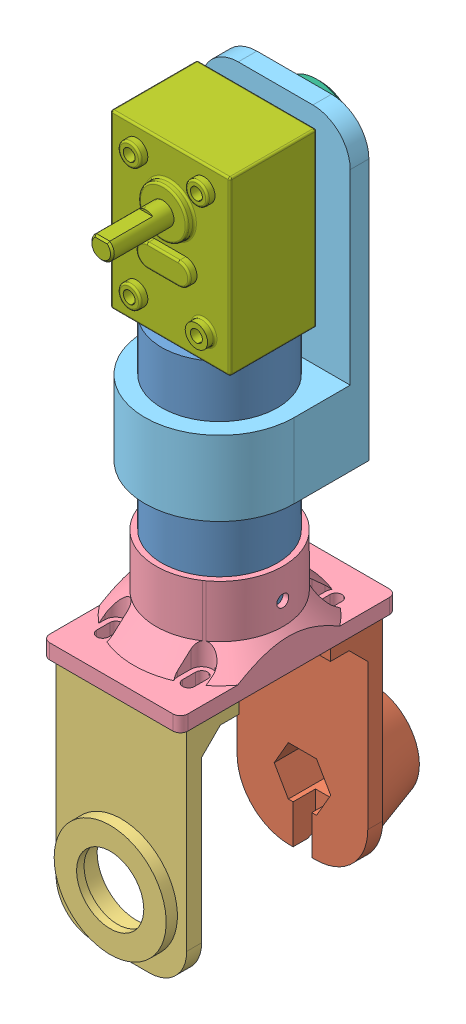
SolidWorks assembly extraLink, configuration По умолчанию. Lengths in mm.
Overall size (40 182 81.54).
7 component instances, 7 part files, 17 mates.
Components (placement in the parent):
- tube2-1: tube2 [По умолчанию] at origin size (31 70 31)
- shaftClamp-1: shaftClamp [По умолчанию] at (-0.0494 -35 -26.25) x (0 1 0) z (1 0 0) size (62 30 35)
- upperBearingClamp-1: upperBearingClamp [По умолчанию] at (-0.0494 -35 26.25) x (0 1 0) z (-1 0 0) size (62 17 35)
- newTubeHolder-1: newTubeHolder [По умолчанию] at (0 -4 0) x (0 0 -1) z (1 0 0) size (58 24 37)
- bearingHolder-2: bearingHolder [По умолчанию] at (0 36 0) x (0 0 -1) z (1 0 0) size (44.5 80 40)
- подшипник-1: подшипник [По умолчанию] at (0 101 -27) x (0.388832 0.921309 0) z (0.921309 -0.388832 0) size (21 5 21)
- двигатель4-1: двигатель4 [По умолчанию] at (0 36.2 0) x (-1 0 0) z (0 0 -1) size (32 79.8 43.9)
Mates (geometry in assembly coordinates):
- Концентричный2: concentric aligned: cylinder of tube2-1 through (0 70 0) axis (0 -1 0) radius 15.5; cylinder of newTubeHolder-1 through (0 20 0) axis (0 -1 0) radius 17
- Совпадение2: coincident anti-aligned: plane of tube2-1 through (0 0 0) normal (0 -1 0); plane of newTubeHolder-1 through (0 0 0) normal (0 1 0)
- Концентричный3: concentric aligned: circle of upperBearingClamp-1; circle of newTubeHolder-1
- Концентричный4: concentric aligned: circle of upperBearingClamp-1; circle of newTubeHolder-1
- Совпадение4: coincident anti-aligned: plane of upperBearingClamp-1 through (-17.5494 -4 22.25) normal (0 1 0); plane of newTubeHolder-1 through (0 -4 0) normal (0 -1 0)
- Концентричный6: concentric aligned: circle of shaftClamp-1; circle of newTubeHolder-1
- Концентричный7: concentric aligned: circle of shaftClamp-1; circle of newTubeHolder-1
- Совпадение8: coincident anti-aligned: plane of shaftClamp-1 through (17.4506 -4 -22.25) normal (0 1 0); plane of newTubeHolder-1 through (0 -4 0) normal (0 -1 0)
- Концентричный12: concentric anti-aligned: circle of bearingHolder-2; circle of подшипник-1
- Совпадение10: coincident anti-aligned: plane of bearingHolder-2 through (0 101 -22) normal (0 0 -1); plane of подшипник-1 through (0 101 -22) normal (0 0 1)
- Концентричный14: concentric aligned: cylinder of tube2-1 through (0 70 0) axis (0 -1 0) radius 15.5; cylinder of двигатель4-1 through (0 70 0) axis (0 -1 0) radius 12.2
- Параллельность1: parallel anti-aligned: plane of bearingHolder-2 through (-20 116 -15) normal (0 0 1); plane of двигатель4-1 through (16 116 -10) normal (0 0 -1)
- Совпадение12: coincident anti-aligned: plane of tube2-1 through (0 70 0) normal (0 1 0); plane of двигатель4-1 through (0 70 0) normal (0 -1 0)
- Параллельность2: parallel aligned: plane of shaftClamp-1 through (-0.0494 -35 -26.25) normal (0 0 -1); plane of bearingHolder-2 through (-20 56 -20) normal (0 0 -1)
- Концентричный15: concentric aligned: cylinder of tube2-1 through (0 70 0) axis (0 -1 0) radius 15.5; cylinder of bearingHolder-2 through (0 56 0) axis (0 -1 0) radius 15.5
- Концентричный16: concentric anti-aligned: cylinder of bearingHolder-2 through (0 101 20) axis (0 0 -1) radius 1.5; circle of двигатель4-1
- Параллельность3: parallel anti-aligned: plane of upperBearingClamp-1 through (-17.5494 -4 22.25) normal (-1 0 0); plane of assembly through (0 0 0) normal (1 0 0)
